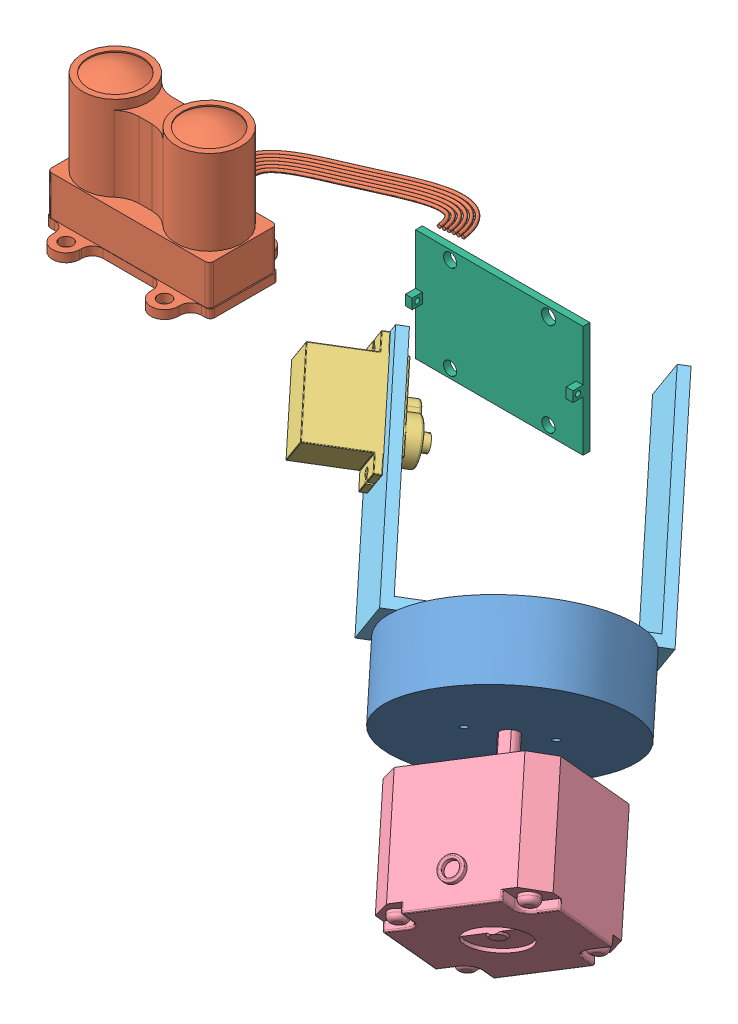
SolidWorks assembly Assem1, configuration Default. Lengths in mm.
Overall size (168.11 165.54 129.74).
6 component instances, 6 part files, 8 mates.
Components (placement in the parent):
- gear-1: gear [Default] at (77.2371 155.0898 188.3926) x (0.60745 -0.240964 -0.756929) z (0.541544 -0.571503 0.616534) size (60 60 20)
- Lidar-Lite-V3-1: Lidar-Lite-V3 [Default] at (-12.9259 219.5784 202.4957) size (74.48 42.89 67.86)
- ServoMotor-1: ServoMotor [Default] at (31.2396 190.0289 185.2743) x (-0.541544 0.571503 -0.616534) z (-0.58115 -0.784424 -0.216667) size (32 29 12)
- stepper motor from datasheet-1: stepper motor from datasheet [Default] at (94.9474 136.2647 208.7265) x (-0.840504 -0.353399 0.410686) z (-0.541544 0.571503 -0.616534) size (42.06 43.63 53.04)
- uclamp-1: uclamp [Default] at (87.417 141.9721 162.4254) x (-0.60745 0.240964 0.756929) z (-0.58115 -0.784424 -0.216667) size (64 63 20)
- lidarbase-1: lidarbase [Default] at (38.2589 194.8512 145.0779) size (49.5 33 5)
Mates (geometry in assembly coordinates):
- Concentric4: concentric anti-aligned: circle of gear-1; circle of uclamp-1
- Concentric5: concentric anti-aligned: circle of gear-1; circle of uclamp-1
- Coincident9: coincident anti-aligned: plane of gear-1 through (77.2371 155.0898 188.3926) normal (-0.541544 0.571503 -0.616534); plane of uclamp-1 through (63.6102 170.6449 214.781) normal (0.541544 -0.571503 0.616534)
- Parallel2: parallel anti-aligned: plane of gear-1 through (88.068 143.6597 200.7233) normal (0.541544 -0.571503 0.616534); plane of stepper motor from datasheet-1 through (112.2446 128.1334 185.9957) normal (-0.541544 0.571503 -0.616534)
- Lock1: lock: unknown of gear-1; unknown of stepper motor from datasheet-1
- Coincident14: coincident anti-aligned: plane of ServoMotor-1 through (31.0996 192.1615 205.6212) normal (0.58115 0.784424 0.216667); plane of uclamp-1 through (35.7523 198.4539 170.3603) normal (-0.58115 -0.784424 -0.216667)
- Coincident16: coincident anti-aligned: plane of ServoMotor-1 through (25.0759 197.3337 175.3602) normal (0.60745 -0.240964 -0.756929); plane of uclamp-1 through (29.4929 206.6496 175.9393) normal (-0.60745 0.240964 0.756929)
- Coincident17: coincident anti-aligned: plane of ServoMotor-1 through (31.0996 192.1615 205.6212) normal (0.541544 -0.571503 0.616534); plane of uclamp-1 through (44.6213 180.7079 183.1272) normal (-0.541544 0.571503 -0.616534)
